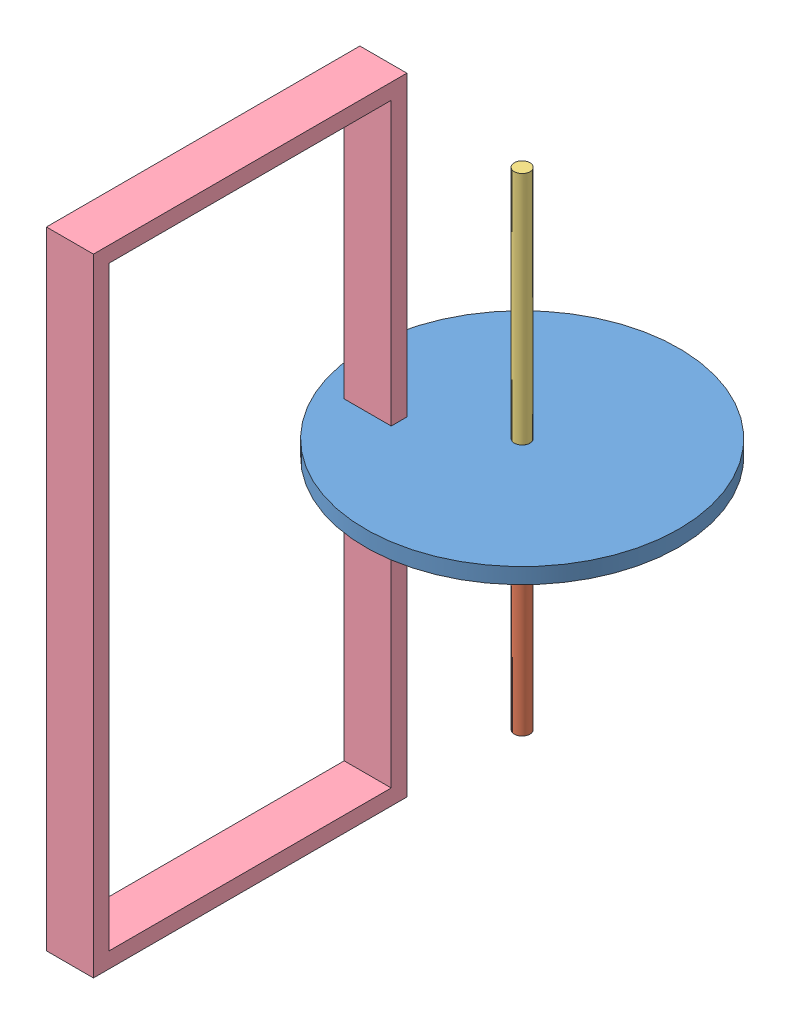
SolidWorks assembly Assem3, configuration Default. Lengths in mm.
Overall size (200 400 324.81).
5 component instances, 4 part files, 1 mates.
Components (placement in the parent):
- Assembly 1-1: Assembly 1 [Default] at (174.3904 -11.1521 124.4189) x (-1 0 0) z (0 1 0) size (200 200 310.83)
  - Disc-1: Disc [Default] at (44.3093 114.1571 157.8814) size (200 200 10)
  - Pipe 1-1: Pipe 1 [Default] at (44.3093 119.1571 82.0492) x (0 0 -1) z (1 0 0) size (150 10 10)
  - Pipe 2-1: Pipe 2 [Default] at (39.6906 112.2419 242.8814) x (0 0 -1) z (-0.383049 0.923728 0) size (150 10 10)
- magnet-1: magnet [Default] at (51.341 346.7292 263.3832) x (0 0 -1) z (1 0 0) size (200 400 30)
Mates (geometry in assembly coordinates):
- Coincident1: coincident: circle of assembly; plane of assembly; circle of Assembly 1-1/Disc-1; plane of magnet-1 through (81.341 156.7292 263.3832) normal (0 -1 0)
